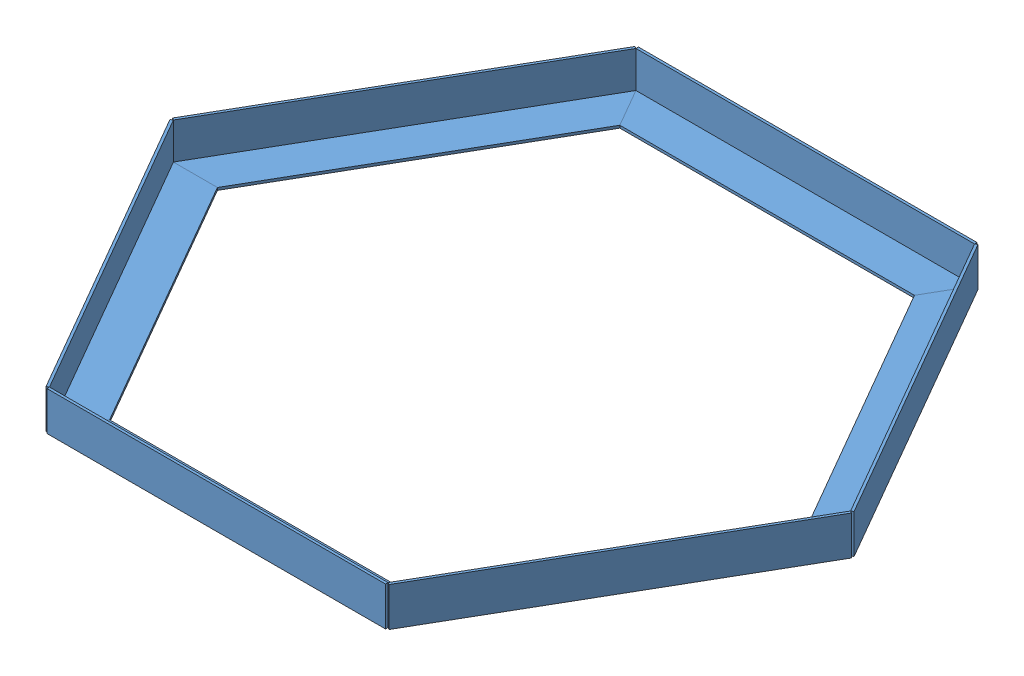
SolidWorks assembly Assem1, configuration Default. Lengths in mm.
Overall size (402.6 23.01 349.41).
6 component instances, 1 part files, 5 mates.
Components (placement in the parent):
- l-bottom-17: l-bottom [Default] at (-23.6892 133.5737 -3.5087) size (200 23.01 24.01)
- l-bottom-21: l-bottom [Default] at (145.9207 133.5737 -56.146) x (0.5 0 -0.866025) z (0.866025 0 0.5) size (200 23.01 24.01)
- l-bottom-22: l-bottom [Default] at (-154.0793 133.5737 -124.0765) x (0.5 0 0.866025) z (-0.866025 0 0.5) size (200 23.01 24.01)
- l-bottom-23: l-bottom [Default] at (-114.8596 133.5737 -297.2816) x (-0.5 0 0.866025) z (-0.866025 0 -0.5) size (200 23.01 24.01)
- l-bottom-24: l-bottom [Default] at (54.7502 133.5737 -349.9189) x (-1 0 0) z (0 0 -1) size (200 23.01 24.01)
- l-bottom-25: l-bottom [Default] at (185.1404 133.5737 -229.3511) x (-0.5 0 -0.866025) z (0.866025 0 -0.5) size (200 23.01 24.01)
Mates (geometry in assembly coordinates):
- Coincident3: coincident: point of l-bottom-22; point of l-bottom-23
- Coincident4: coincident: point of l-bottom-23; point of l-bottom-24
- Coincident5: coincident: point of l-bottom-24; point of l-bottom-25
- Coincident6: coincident: point of l-bottom-21; point of l-bottom-25
- Coincident7: coincident: point of l-bottom-17; point of l-bottom-21
